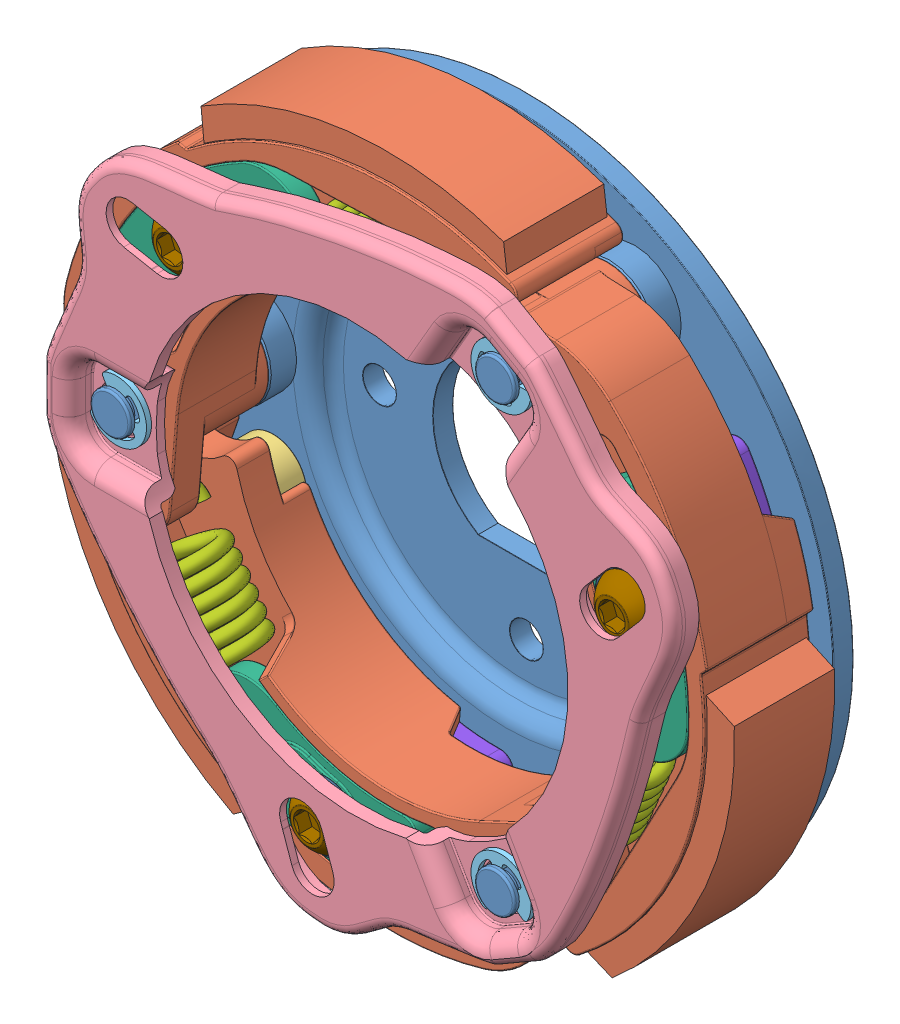
SolidWorks assembly CLAssembly, configuration Default. Lengths in mm.
Overall size (134.83 134.51 29.83).
26 component instances, 10 part files, 20 mates.
Components (placement in the parent):
- frix1-1: frix1 [Default] at (3.6079 -6.0485 93.5) size (98 98 27)
- coupling jaws-2: coupling jaws [Default] at (3.2077 -6.6414 108.5) x (0.753508 0.657438 0) z (0 0 1) size (83.94 39.62 16.05)
- CLpart7-1: CLpart7 [Default] at (6.9616 32.2839 96.5) x (-0.923728 -0.383049 0) z (0 0 -1) size (10 10 6)
- coupling jaws-3: coupling jaws [Default] at (3.2946 -5.4056 108.5) x (0.192604 -0.981277 0) z (0 0 1) size (83.94 39.62 16.05)
- coupling jaws-4: coupling jaws [Default] at (4.3214 -6.0987 108.5) x (-0.946113 0.323838 0) z (0 0 1) size (83.94 39.62 16.05)
- CLpart7-2: CLpart7 [Default] at (35.1279 -28.1192 96.5) x (0.130134 0.991496 0) z (0 0 -1) size (10 10 6)
- CLpart7-3: CLpart7 [Default] at (-31.2658 -22.3104 96.5) x (0.793594 -0.608447 0) z (0 0 -1) size (10 10 6)
- CLPart3-1: CLPart3 [Default] at (0.797 -4.221 113.25) x (0.866025 -0.5 0) z (0 0 1) size (99.02 98.15 5.55)
- seeger-1: seeger [Default] at (-34.7921 -6.0485 109.75) x (0.299888 0.953975 0) z (0 0 1) size (9 7.62 0.75)
- seeger-2: seeger [Default] at (22.8079 27.2068 109.75) x (0.676222 -0.736698 0) z (0 0 1) size (9 7.62 0.75)
- seeger-3: seeger [Default] at (22.8079 -39.3039 109.75) x (-0.97611 -0.217277 0) z (0 0 1) size (9 7.62 0.75)
- CLPart5-1: CLPart5 [Default] at (3.2078 -6.6419 104.5) x (0.830975 0.55631 0) z (0 0 1) size (35.09 17.35 4.51)
- CLPart5-2: CLPart5 [Default] at (4.3219 -6.0984 104.5) x (-0.897266 0.44149 0) z (0 0 1) size (35.09 17.35 4.51)
- CLPart5-3: CLPart5 [Default] at (3.2941 -5.4053 104.5) x (0.066291 -0.9978 0) z (0 0 1) size (35.09 17.35 4.51)
- spring-2: spring [Default] at (5.2721 29.8885 106.3913) x (-0.079986 0.792036 0.605212) z (0.080268 -0.600068 0.795912) size (10 29.17 11.55)
- spring-3: spring [Default] at (33.8982 -25.4583 106.3913) x (0.725916 -0.326748 0.605212) z (-0.559808 0.23052 0.795912) size (10 29.17 11.55)
- spring-4: spring [Default] at (-28.3466 -22.5758 106.3913) x (-0.64593 -0.465287 0.605212) z (0.47954 0.369548 0.795912) size (10 29.17 11.55)
- CLPart6-1: CLPart6 [Default] at (3.2077 -6.6414 92.5) x (0.865283 0.501284 0) z (0 0 1) size (35.22 17.41 4)
- CLPart6-2: CLPart6 [Default] at (4.3214 -6.0987 92.5) x (-0.866766 0.498715 0) z (0 0 1) size (35.22 17.41 4)
- CLPart6-3: CLPart6 [Default] at (3.2946 -5.4056 92.5) x (0.001483 -0.999999 0) z (0 0 1) size (35.22 17.41 4)
- CLPart2-1: CLPart2 [Default] at (40.9096 5.8149 109.5) x (-0.923728 -0.383049 0) z (0 0 -1) size (8.96 8.96 22.56)
- CLpart8-1: CLpart8 [Default] at (40.9096 5.8149 109.5) x (-0.923728 -0.383049 0) z (0 0 -1) size (10 10 0.5)
- CLPart2-2: CLPart2 [Default] at (-4.7688 -44.2845 109.5) x (0.130134 0.991496 0) z (0 0 -1) size (8.96 8.96 22.56)
- CLPart2-3: CLPart2 [Default] at (-25.317 20.3239 109.5) x (0.793594 -0.608447 0) z (0 0 -1) size (8.96 8.96 22.56)
- CLpart8-2: CLpart8 [Default] at (-4.7688 -44.2845 109.5) x (0.130134 0.991496 0) z (0 0 -1) size (10 10 0.5)
- CLpart8-3: CLpart8 [Default] at (-25.317 20.3239 109.5) x (0.793594 -0.608447 0) z (0 0 -1) size (10 10 0.5)
Mates (geometry in assembly coordinates):
- Coincidente2: coincident anti-aligned: plane of frix1-1 through (-34.7921 -6.0485 94.5) normal (0 0 1); plane of coupling jaws-2 through (-34.7924 -6.0482 94.5) normal (0 0 -1)
- Concentrico4: concentric anti-aligned: cylinder of frix1-1 through (-34.7921 -6.0485 108.5) axis (0 0 -1) radius 4; cylinder of coupling jaws-2 through (-34.7924 -6.0482 98.5) axis (0 0 1) radius 4
- Distanza1: distance = 0.5 mm anti-aligned: cylinder of frix1-1 through (22.8079 27.2068 94.5) axis (0 0 -1) radius 7; plane of coupling jaws-2 through (-8.3967 23.0716 92.5) normal (0.363789 -0.931481 0)
- Coincidente3: coincident anti-aligned: plane of frix1-1 through (52.6079 -6.0485 90.5) normal (0 0 1); plane of CLpart7-1 through (6.9612 32.2842 90.5) normal (0 0 -1)
- Concentrico5: concentric aligned: cylinder of coupling jaws-2 through (6.9612 32.2842 92.5) axis (0 0 1) radius 5; cylinder of CLpart7-1 through (6.9612 32.2842 90.5) axis (0 0 1) radius 5
- Coincidente4: coincident anti-aligned: plane of frix1-1 through (-34.7921 -6.0485 108.5) normal (0 0 1); plane of CLPart3-1 through (-49.5694 -9.4688 108.5) normal (0 0 -1)
- Concentrico6: concentric anti-aligned: cylinder of frix1-1 through (-34.7921 -6.0485 108.5) axis (0 0 -1) radius 3; cylinder of CLPart3-1 through (-34.7921 -6.0485 93.25) axis (0 0 1) radius 3.2
- Concentrico7: concentric anti-aligned: cylinder of frix1-1 through (22.8079 27.2068 108.5) axis (0 0 -1) radius 3; cylinder of CLPart3-1 through (22.8079 27.2068 93.25) axis (0 0 1) radius 3.2
- Coincidente5: coincident anti-aligned: plane of CLPart3-1 through (-35.3634 -8.4575 109.75) normal (0 0 1); plane of seeger-1 through (-36.3908 -2.3819 109.75) normal (0 0 -1)
- Concentrico8: concentric aligned: cylinder of frix1-1 through (-34.7921 -6.0485 108.5) axis (0 0 -1) radius 2; cylinder of seeger-1 through (-34.7921 -6.0485 110.5) axis (0 0 -1) radius 2.5
- Coincidente8: coincident anti-aligned: plane of coupling jaws-2 through (3.2029 -6.6419 104.5) normal (0 0 1); plane of CLPart5-1 through (-8.9309 30.9852 104.5) normal (0 0 -1)
- Concentrico13: concentric anti-aligned: cylinder of coupling jaws-2 through (3.2029 -6.6419 104.5) axis (0 0 1) radius 33; cylinder of CLPart5-1 through (3.2029 -6.6419 108.5) axis (0 0 -1) radius 33
- Concentrico14: concentric anti-aligned: cylinder of coupling jaws-2 through (-25.3174 20.3239 98.5) axis (0 0 1) radius 2.5; cylinder of CLPart5-1 through (-25.3171 20.3236 108.5) axis (0 0 -1) radius 2.5
- Blocca3: lock: unknown of CLPart5-1; unknown of spring-2
- Coincidente11: coincident anti-aligned: plane of coupling jaws-2 through (-30.8128 1.5772 96.5) normal (0 0 -1); plane of CLPart6-1 through (3.2073 -6.6411 96.5) normal (0 0 1)
- Concentrico15: concentric aligned: cylinder of coupling jaws-2 through (3.2073 -6.6411 96.5) axis (0 0 -1) radius 32.9946; cylinder of CLPart6-1 through (3.2073 -6.6411 96.5) axis (0 0 -1) radius 32.9946
- Coincidente12: coincident anti-aligned: plane of CLPart5-3 through (3.2945 -5.4052 109) normal (0 0 1); plane of CLpart8-1 through (40.9093 5.8151 109) normal (0 0 -1)
- Concentrico16: concentric anti-aligned: cylinder of CLPart5-3 through (40.9093 5.8151 108.5) axis (0 0 -1) radius 2.5; cylinder of CLpart8-1 through (40.9093 5.8151 109) axis (0 0 1) radius 3
- Coincidente13: coincident anti-aligned: plane of CLPart2-1 through (40.9093 5.8151 109.5) normal (0 0 -1); plane of CLpart8-1 through (40.9093 5.8151 109.5) normal (0 0 1)
- Concentrico17: concentric anti-aligned: cylinder of CLPart5-3 through (40.9089 5.815 108.5) axis (0 0 -1) radius 2.5; cylinder of CLPart2-1 through (40.9096 5.8149 89.5) axis (0 0 1) radius 2.5
